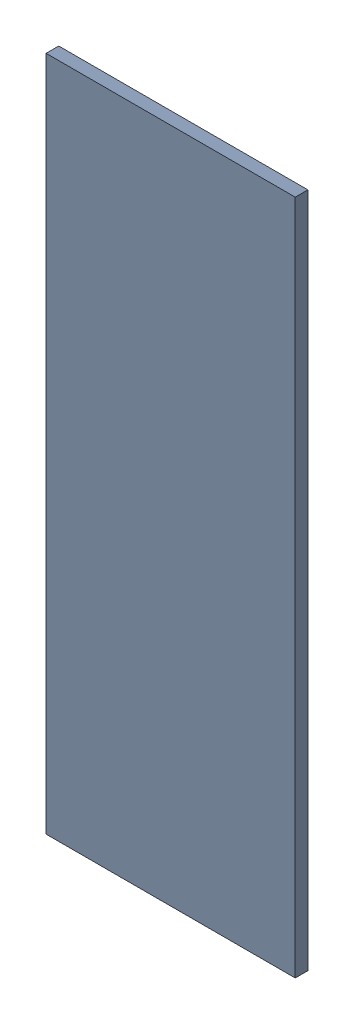
SolidWorks assembly Pad RAK4600-40(19.975mm,31.391mm) on Top Layer, configuration Predeterminado. Lengths in mm.
Overall size (0.7 1.9 0.04).
2 component instances, 1 part files, 0 mates.
Components (placement in the parent):
- Pad RAK4600-40(19.975mm,31.391mm) on Top Layer-1-1: Pad RAK4600-40(19.975mm,31.391mm) on Top Layer-1 [Predeterminado] at (-68.317 -44.187 -0.0457) size (0.7 1.9 0.04)
  - Pad RAK4600-40(19.975mm,31.391mm) on Top Layer-Part-1-1: Pad RAK4600-40(19.975mm,31.391mm) on Top Layer-Part-1 [Predeterminado] at origin size (0.7 1.9 0.04)
